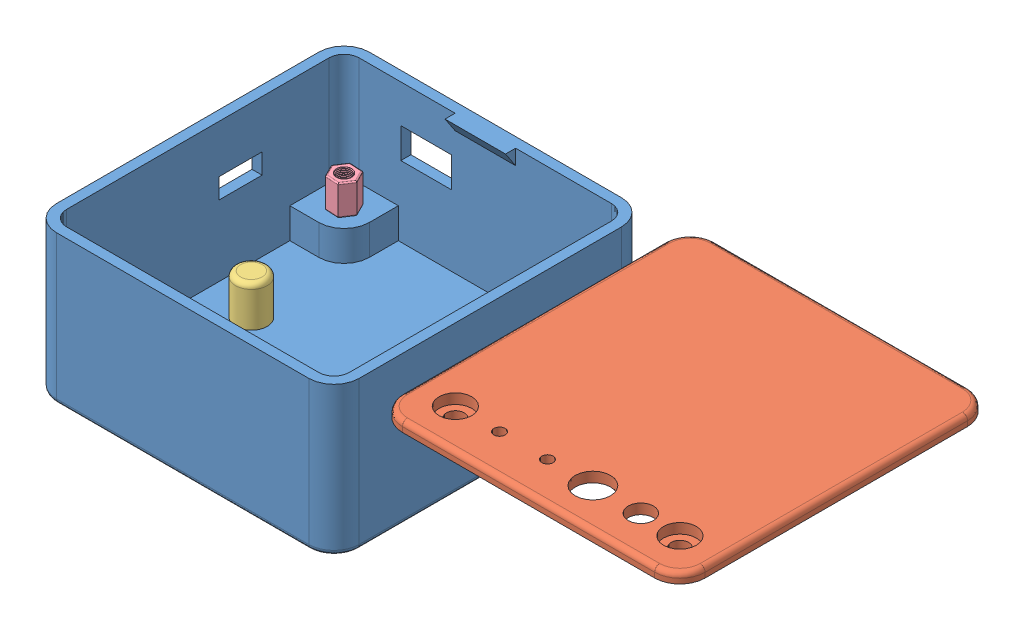
SolidWorks assembly base-station, configuration Default. Lengths in mm.
Overall size (128.56 34.09 62).
8 component instances, 5 part files, 22 mates.
Components (placement in the parent):
- Bottom case-1: Bottom case [Default] at origin size (60 29.5 62)
- lid-1: lid [Default] at (68.5568 29.5 0) size (60 6 62)
- button-1: button [Default] at (5.4404 26.0896 22.8108) x (-1 0 0.000001) z (-0.000001 0 -1) size (6.25 8 6.25)
- Board.step-1: Board.step [Default] at (98.4 15.5896 -0.8801) x (1 0 -0.000001) z (0 1 0)
- 6+6 M3 Standoff-1: 6+6 M3 Standoff [Default] at (-22.25 14 23.25) x (-0.837169 0 -0.546944) z (-0.546944 0 0.837169) size (4.65 12 5.37)
- 6+6 M3 Standoff-2: 6+6 M3 Standoff [Default] at (22.25 14 23.25) x (-0.837169 0 -0.546944) z (-0.546944 0 0.837169) size (4.65 12 5.37)
- 6+6 M3 Standoff-4: 6+6 M3 Standoff [Default] at (22.25 14 -23.25) x (-0.359375 0 -0.933193) z (-0.933193 0 0.359375) size (4.65 12 5.37)
- 6+6 M3 Standoff-5: 6+6 M3 Standoff [Default] at (-22.25 14 -23.25) x (-0.837169 0 -0.546944) z (-0.546944 0 0.837169) size (4.65 12 5.37)
Mates (geometry in assembly coordinates):
- Concentric1: concentric aligned: cylinder of Bottom case-1 through (-22.25 8 -23.25) axis (0 -1 0) radius 1.375; circle of ?
- Parallel7: parallel: plane of Bottom case-1 through (-28 -80.6226 0) normal (1 0 0); line of ? through (-27.33 15.5896 25.01) axis (0 0 -1)
- Coincident7: coincident anti-aligned: plane of Bottom case-1 through (25 29.5 -26) normal (0 1 0); plane of lid-1 through (93.5568 29.5 26) normal (0 -1 0)
- Coincident8: coincident aligned: plane of Bottom case-1 through (-25 29.5 31) normal (0 0 1); plane of lid-1 through (93.5568 31.5 31) normal (0 0 1)
- Coincident9: coincident: plane of ? through (8.7341 28.7896 23.4258) normal (0 1 0); plane of button-1 through (5.4404 29.0896 22.8108) normal (0 -1 0)
- Coincident10: coincident: plane of ? through (4.3154 29.0896 21.9258) normal (-1 0 -0.000001); plane of button-1 through (4.3154 29.0896 24.4358) normal (1 0 -0.000001)
- Coincident11: coincident: plane of ? through (6.3154 29.0896 24.9258) normal (-0.000001 0 1); plane of button-1 through (6.5654 29.0896 24.4358) normal (-0.000001 0 -1)
- Distance2: distance = 6 mm: plane of ? through (-27.33 14 -24.52) normal (0 -1 0); plane of Bottom case-1 through (0 8 0) normal (0 1 0)
- Concentric2: concentric aligned: cylinder of Bottom case-1 through (22.25 8 -23.25) axis (0 -1 0) radius 1.375; circle of 6+6 M3 Standoff-4
- Concentric4: concentric aligned: cylinder of Bottom case-1 through (22.25 8 23.25) axis (0 -1 0) radius 1.375; circle of 6+6 M3 Standoff-2
- Concentric5: concentric aligned: cylinder of Bottom case-1 through (-22.25 8 23.25) axis (0 -1 0) radius 1.375; circle of 6+6 M3 Standoff-1
- Concentric6: concentric aligned: cylinder of Bottom case-1 through (-22.25 8 -23.25) axis (0 -1 0) radius 1.375; circle of 6+6 M3 Standoff-5
- Coincident12: coincident anti-aligned: plane of Bottom case-1 through (0 8 0) normal (0 1 0); plane of 6+6 M3 Standoff-4 through (22.25 8 -23.25) normal (0 -1 0)
- Coincident13: coincident anti-aligned: plane of Bottom case-1 through (0 8 0) normal (0 1 0); plane of 6+6 M3 Standoff-5 through (-22.25 8 -23.25) normal (0 -1 0)
- Coincident14: coincident anti-aligned: plane of Bottom case-1 through (0 8 0) normal (0 1 0); plane of 6+6 M3 Standoff-1 through (-22.25 8 23.25) normal (0 -1 0)
- Coincident15: coincident anti-aligned: plane of Bottom case-1 through (0 8 0) normal (0 1 0); plane of 6+6 M3 Standoff-2 through (22.25 8 23.25) normal (0 -1 0)
- Coincident16: coincident anti-aligned: circle of Board.step-1; plane of 6+6 M3 Standoff-4 through (22.25 14 -23.25) normal (0 1 0)
- Parallel8: parallel anti-aligned: plane of Bottom case-1 through (0 -80.6226 29) normal (0 0 -1); plane of Board.step-1 through (23.47 15.5896 28.33) normal (0 0 1)
- Concentric7: concentric anti-aligned: circle of Board.step-1; circle of 6+6 M3 Standoff-1
- Coincident18: coincident anti-aligned: plane of button-1 through (5.4404 26.0896 22.8108) normal (0 -1 0); plane of Board.step-1 through (5.3154 26.0896 22.9358) normal (0 1 0)
- Coincident19: coincident anti-aligned: plane of button-1 through (4.3154 29.0896 24.4358) normal (1 0 -0.000001); plane of Board.step-1 through (4.3154 29.0896 21.4358) normal (-1 0 0.000001)
- Coincident20: coincident anti-aligned: plane of button-1 through (6.5654 29.0896 24.4358) normal (-0.000001 0 -1); plane of Board.step-1 through (6.3154 29.0896 24.4358) normal (0.000001 0 1)
